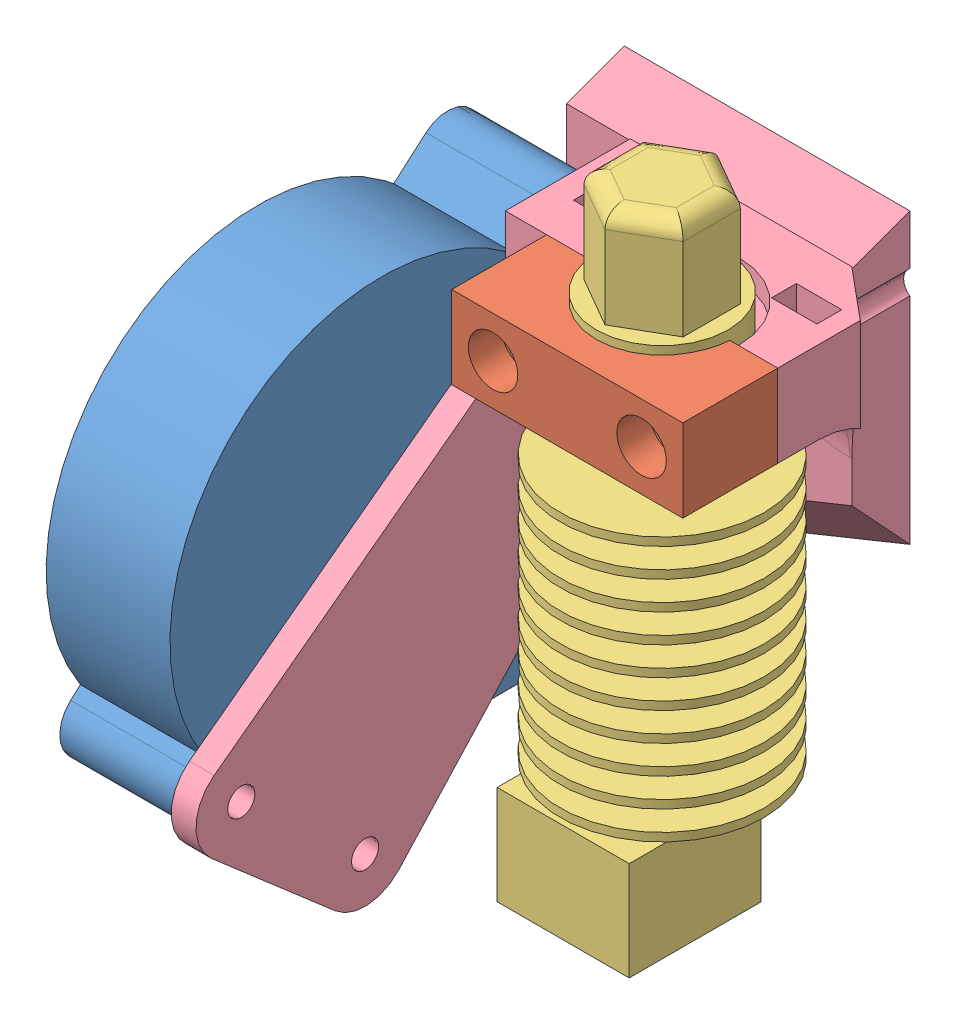
SolidWorks assembly Mont3, configuration Valor predeterminado. Lengths in mm.
Overall size (48 79 63).
4 component instances, 4 part files, 8 mates.
Components (placement in the parent):
- Cooler (50x50x15)-1: Cooler (50x50x15) [Valor predeterminado] at (59.7368 23.9067 61.75) x (0 1 0) z (-1 0 0) size (51.8 53 15)
- hotend lock-1: hotend lock [Valor predeterminado] at (78.7368 43.9067 46.25) x (1 0 0) z (0 -1 0) size (28 11.5 10)
- hotend-1: hotend [Valor predeterminado] at (78.7368 -1.7525 46.75) size (24.7 79 24.7)
- Printer_tool-1: Printer_tool [Valor predeterminado] at (69.4368 35.9067 24.75) size (40.6 64 62.5)
Mates (geometry in assembly coordinates):
- Concêntrico2: concentric: cylinder of hotend lock-1 through (87.7368 43.9067 54.25) axis (0 0 1) radius 3; cylinder of Printer_tool-1 through (87.7368 43.9067 24.75) axis (0 0 1) radius 1.75
- Concêntrico3: concentric: cylinder of hotend lock-1 through (69.7368 43.9067 54.25) axis (0 0 1) radius 3; cylinder of Printer_tool-1 through (69.7368 43.9067 24.75) axis (0 0 1) radius 1.75
- Coincidente1: coincident anti-aligned: plane of hotend lock-1 through (92.7368 41.4067 46.75) normal (0 0 -1); plane of Printer_tool-1 through (59.7368 38.9067 46.75) normal (0 0 1)
- Concêntrico4: concentric: cylinder of hotend-1 through (78.7368 49.9067 46.75) axis (0 1 0) radius 5.5; cylinder of Printer_tool-1 through (78.7368 46.4067 46.75) axis (0 1 0) radius 9.25
- Coincidente2: coincident anti-aligned: plane of hotend-1 through (84.2368 46.4067 46.75) normal (0 -1 0); plane of Printer_tool-1 through (78.7368 46.4067 46.75) normal (0 1 0)
- Concêntrico5: concentric: cylinder of Cooler (50x50x15)-1 through (44.7368 43.9067 38.75) axis (1 0 0) radius 2.25; cylinder of Printer_tool-1 through (69.7368 43.9067 38.75) axis (-1 0 0) radius 1.65
- Concêntrico6: concentric: cylinder of Cooler (50x50x15)-1 through (44.7368 5.9067 81.75) axis (1 0 0) radius 2.25; cylinder of Printer_tool-1 through (62.7368 5.9067 81.75) axis (-1 0 0) radius 1.65
- Coincidente3: coincident anti-aligned: plane of Cooler (50x50x15)-1 through (59.7368 23.9067 61.75) normal (1 0 0); plane of Printer_tool-1 through (59.7368 38.9067 31.75) normal (-1 0 0)
